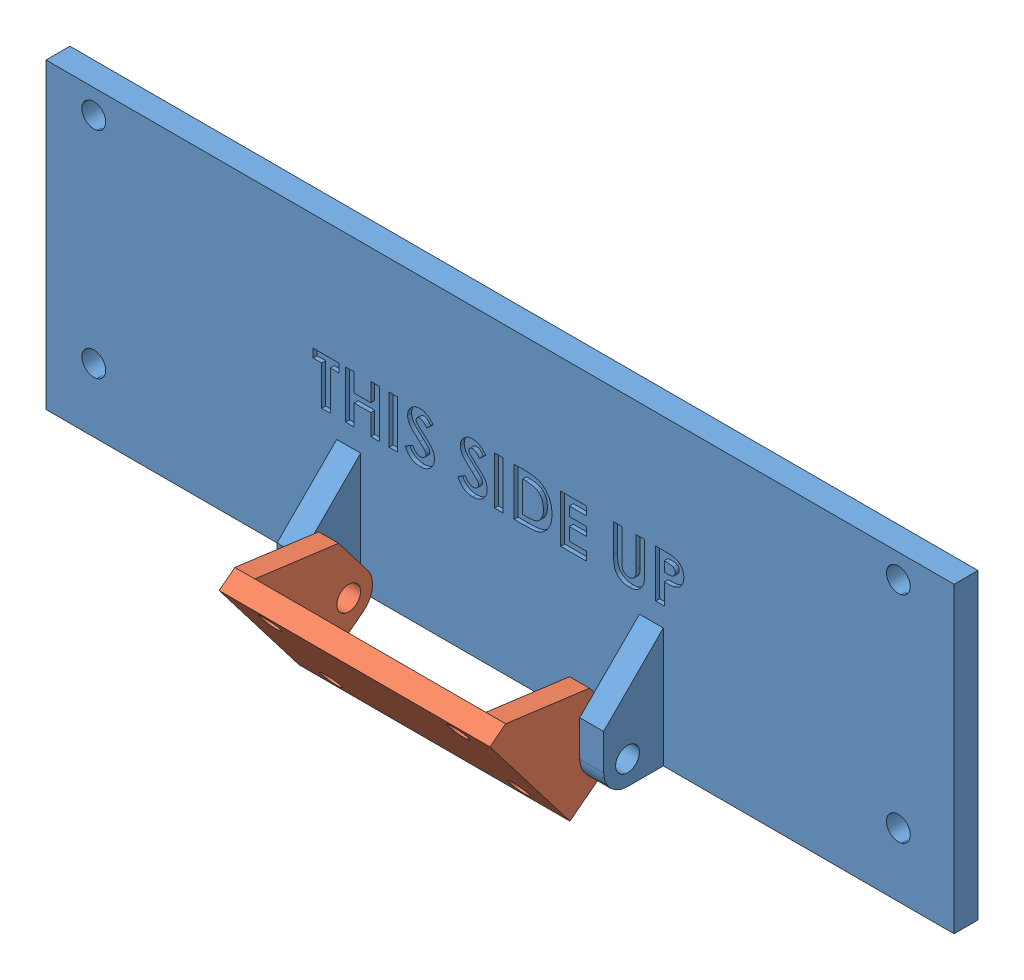
SolidWorks assembly Assem1, configuration Default. Lengths in mm.
Overall size (114 41.64 21.27).
2 component instances, 2 part files, 2 mates.
Components (placement in the parent):
- front-1: front [Default] at (1.1361 -5.4878 -4.7262) size (114 38 10.5)
- camera-1: camera [Default] at (4.6844 -23.3026 9.0062) x (-1 0 0) z (0 0.60843 -0.793607) size (34 16.5 10)
Mates (geometry in assembly coordinates):
- Concentric1: concentric aligned: circle of front-1; circle of camera-1
- Distance1: distance = 0.5 mm anti-aligned: plane of camera-1 through (21.0629 -11.951 14.5589) normal (1 0 0); plane of front-1 through (21.5629 -22.9268 5.7738) normal (-1 0 0)
